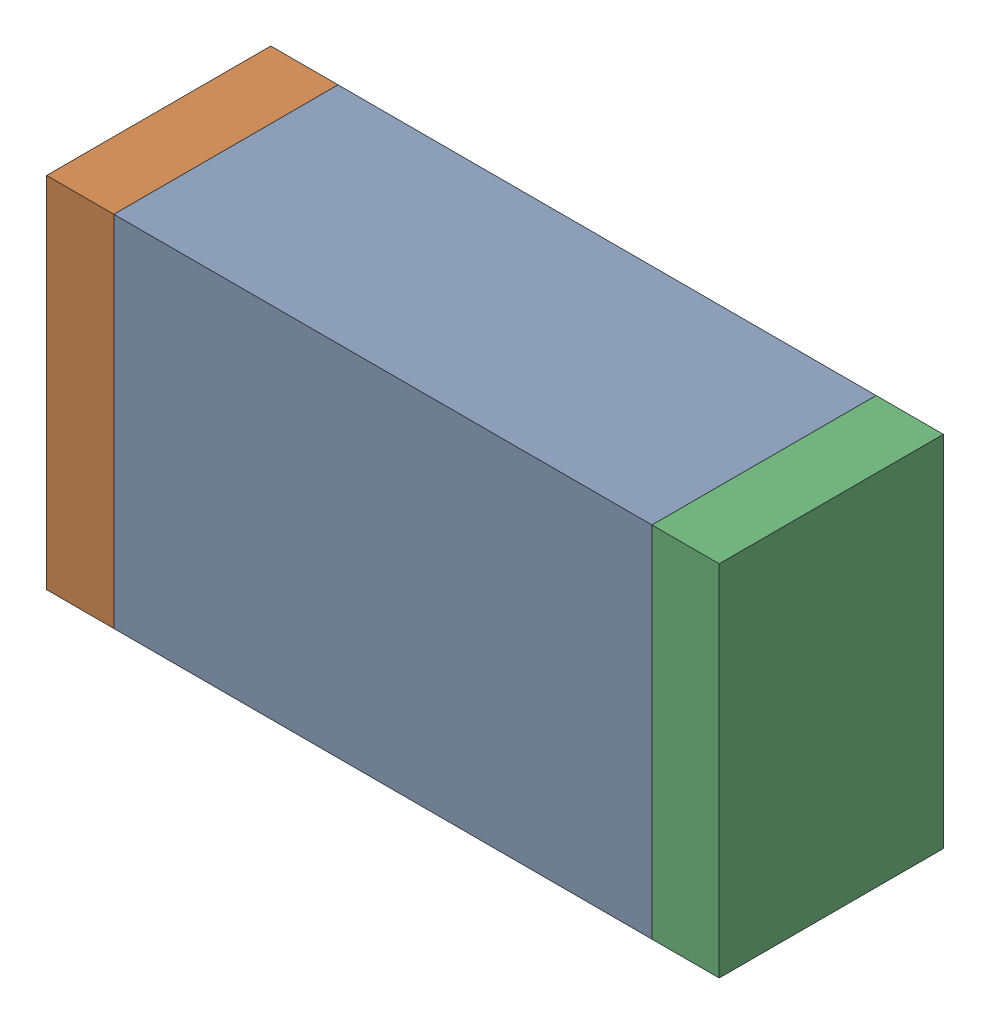
SolidWorks assembly D14, configuration Default. Lengths in mm.
Overall size (1.5 0.8 0.5).
6 component instances, 2 part files, 0 mates.
Components (placement in the parent):
- 836752368-1: 836752368 [Default] at (111.2 30.9 0) size (1.2 0.8 0.5)
  - Extruded-1: Extruded [Default] at origin size (1.2 0.8 0.5)
- 836752496-1: 836752496 [Default] at (110.525 30.9 0) size (0.15 0.8 0.5)
  - Extruded_2-1: Extruded_2 [Default] at origin size (0.15 0.8 0.5)
- 836752496-2: 836752496 [Default] at (111.875 30.9 0) size (0.15 0.8 0.5)
  - Extruded_2-1: Extruded_2 [Default] at origin size (0.15 0.8 0.5)
